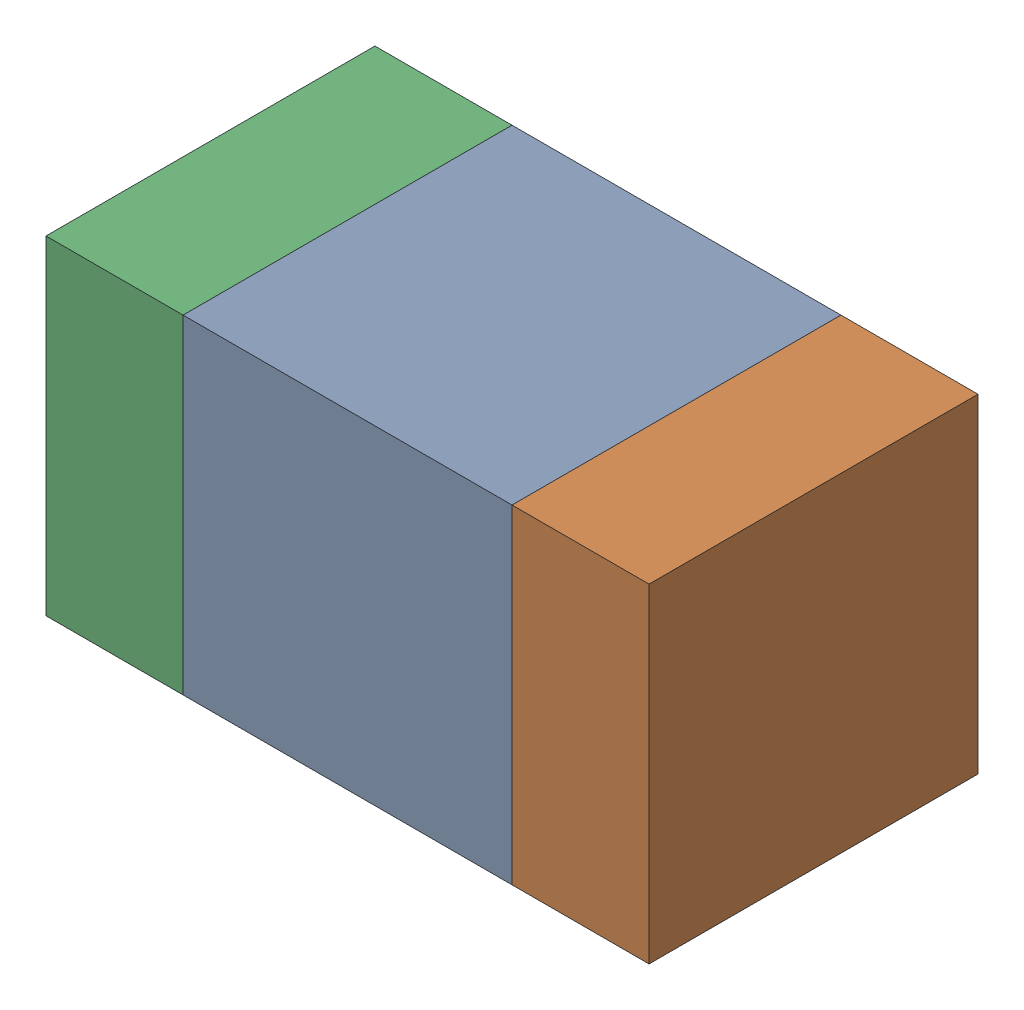
SolidWorks assembly C301_1PCB, configuration Default. Lengths in mm.
Overall size (1.1 0.6 0.6).
6 component instances, 2 part files, 0 mates.
Components (placement in the parent):
- 761606048-1: 761606048 [Default] at (145.8 108.2 0) size (0.6 0.6 0.6)
  - Extruded_9-1: Extruded_9 [Default] at origin size (0.6 0.6 0.6)
- 854785160-1: 854785160 [Default] at (146.225 108.2 0) size (0.25 0.6 0.6)
  - Extruded_19-1: Extruded_19 [Default] at origin size (0.25 0.6 0.6)
- 854785160-2: 854785160 [Default] at (145.375 108.2 0) size (0.25 0.6 0.6)
  - Extruded_19-1: Extruded_19 [Default] at origin size (0.25 0.6 0.6)
